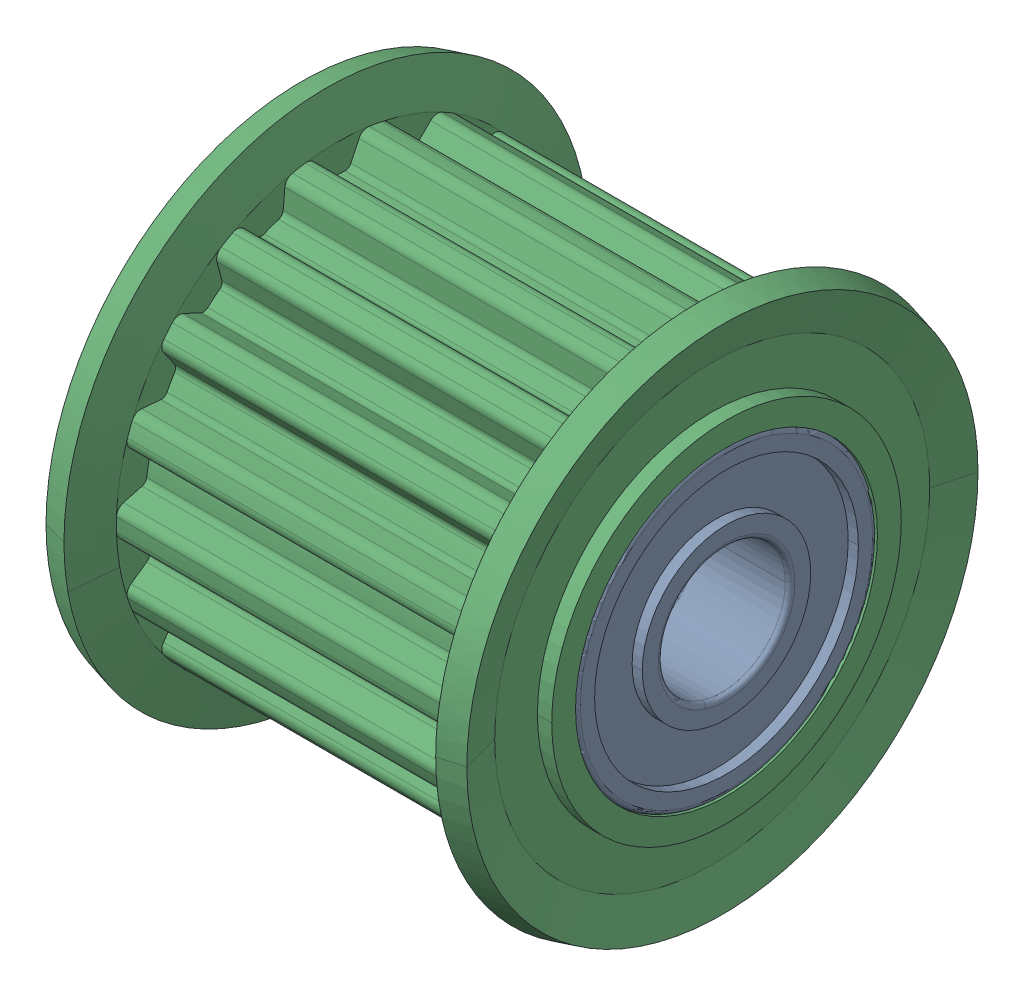
SolidWorks assembly AHTFW18_T5200_8, configuration Default. Lengths in mm.
Overall size (27 33 33).
3 component instances, 2 part files, 0 mates.
Components (placement in the parent):
- AHTFW18_T5200_8_3-1: AHTFW18_T5200_8_3 [Default] at (27 0 0) x (-1 0 0) z (0 0 1) size (6 19 19)
- AHTFW18_T5200_8_3-2: AHTFW18_T5200_8_3 [Default] at origin size (6 19 19)
- AHTFW18_T5200_8_6-1: AHTFW18_T5200_8_6 [Default] at origin size (27 33 33)
